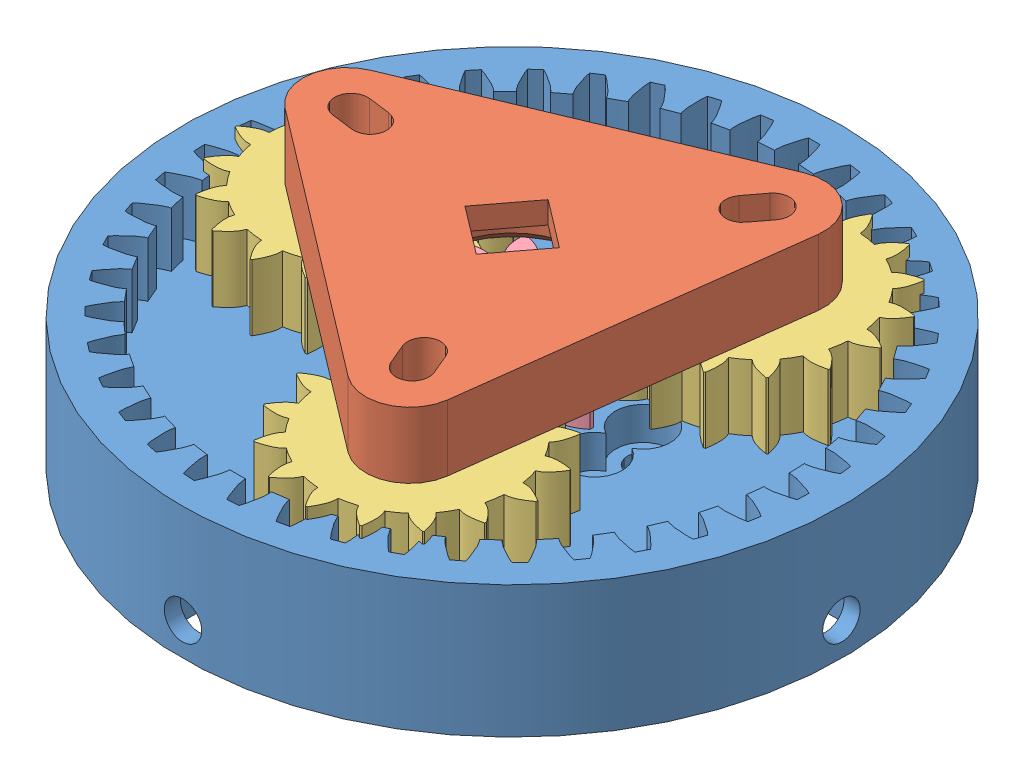
SolidWorks assembly Assem3, configuration Default. Lengths in mm.
Overall size (85.09 24.13 85.09).
8 component instances, 5 part files, 0 mates.
Components (placement in the parent):
- Assem2-1: Assem2 [Default] at origin size (85.09 24.13 85.09)
  - Planetary Gear Box 2.0, RING-1: Planetary Gear Box 2.0, RING [Default] at origin size (85.09 15.24 85.09)
  - Planetary Gear Box 2.0, Coupling-1: Planetary Gear Box 2.0, Coupling [Default] at (0 12.7 0) x (0.795704 0 0.605686) z (-0.605686 0 0.795704) size (48.44 7.62 43.31)
  - Planetary Gear Box 2.0, PLANETS-5: Planetary Gear Box 2.0, PLANETS [Default] at (-20.3428 5.08 -2.5981) x (0.752065 0 0.659089) z (-0.659089 0 0.752065) size (26.67 7.62 26.67)
  - Planetary Gear Box 2.0, PLANETS-6: Planetary Gear Box 2.0, PLANETS [Default] at (12.4214 5.08 -16.3183) x (0.938353 0 0.345678) z (-0.345678 0 0.938353) size (26.67 7.62 26.67)
  - Planetary Gear Box 2.0, PLANETS-7: Planetary Gear Box 2.0, PLANETS [Default] at (7.9214 5.08 18.9164) x (0.938435 0 0.345455) z (-0.345455 0 0.938435) size (26.67 7.62 26.67)
  - Planetary Gear Box 2.0, SUN-1: Planetary Gear Box 2.0, SUN [Default] at (0 12.7 0) x (-0.316304 0 0.948658) z (0.948658 0 0.316304) size (18.98 7.62 18.72)
  - Planetary Gear Box 2.0, SLEEVE-1: Planetary Gear Box 2.0, SLEEVE [Default] at (0 -3.937 0) size (85.34 36.83 85.34) (hidden)
